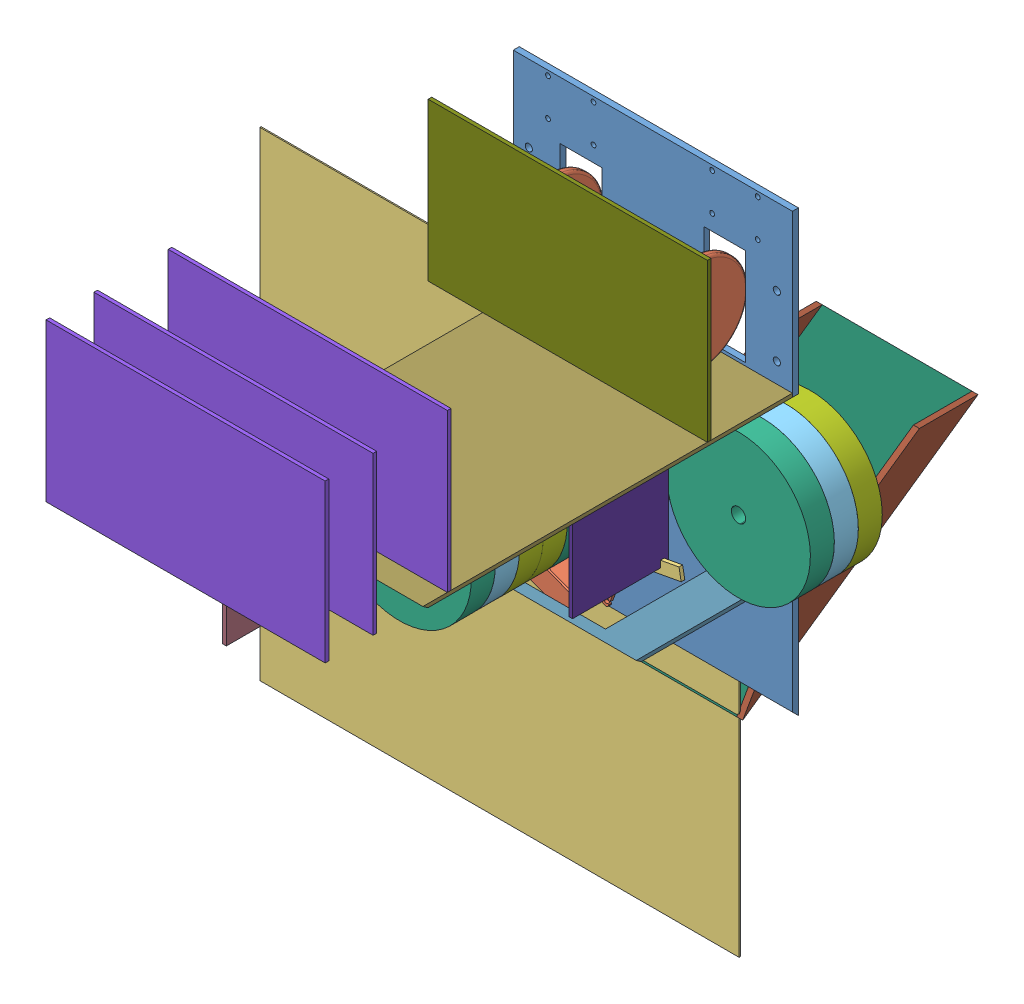
SolidWorks assembly diff_sys4, configuration Default. Lengths in mm.
Overall size (587.66 576.73 602.12).
76 component instances, 41 part files, 74 mates.
Components (placement in the parent):
- diff_base-1: diff_base [Default] at (2.8298 305.3457 326.6792) size (361.16 367.18 5)
- wheel-1: wheel [Default] at (67.3298 304.3457 356.6792) x (0 0.692445 -0.721471) z (-1 0 0) size (80 80 7)
- ground-1: ground [Default] at (-340.1702 216.7923 315.6792) size (400 400 1)
- wheel-2: wheel [Default] at (-52.6702 304.3457 356.6792) x (0 0.692445 -0.721471) z (-1 0 0) size (80 80 7)
- diff_plate-1: diff_plate [Default] at (-5.6702 196.3457 331.6792) size (120 120 3)
- cream_yellow-1: cream_yellow [Default] at (119.3298 196.3457 336.6792) x (0.983664 -0.180016 0) z (0 0 1) size (120 120 20)
- Icing_pink-1: Icing_pink [Default] at (119.3298 196.3457 356.6792) x (0.777887 0.628404 0) z (0 0 1) size (120 120 20)
- sponge_brown-1: sponge_brown [Default] at (119.3298 196.3457 316.6792) size (120 120 20)
- sponge_brown-2: sponge_brown [Default] at (-5.6702 196.3457 334.6792) size (120 120 20)
- Icing_pink-2: Icing_pink [Default] at (-5.6702 196.3457 374.6792) size (120 120 20)
- cream_yellow-2: cream_yellow [Default] at (-5.6702 196.3457 354.6792) x (0.983664 -0.180016 0) z (0 0 1) size (120 120 20)
- sponge_brown-3: sponge_brown [Default] at (-5.6702 196.3457 394.6792) size (120 120 20)
- Icing_pink-3: Icing_pink [Default] at (-5.6702 196.3457 434.6792) size (120 120 20)
- cream_yellow-3: cream_yellow [Default] at (-5.6702 196.3457 414.6792) x (0.983664 -0.180016 0) z (0 0 1) size (120 120 20)
- sponge_brown-5: sponge_brown [Default] at (-5.6702 196.3457 454.6792) x (0.879645 -0.475631 0) z (0 0 1) size (120 120 20)
- diff_layer_3-9: diff_layer_3 [Default] at (-113.6702 393.3457 616.6792) size (233 131.5 3)
- ydlidar x4-1: ydlidar x4 [Défaut] at (33.3597 285.634 646.6792) size (101.5 71 59)
- Raspberry Pi  Camera-1: Raspberry Pi  Camera [Default] at (-15.5914 342.8882 616.6792) x (-1 0 0) z (0 0 -1) size (25 24 6)
- Part11-2: Part11 [Default] at (-53.5079 625.6972 -273.3379) x (1 0 0) z (0 -0.96518 0.261586) size (5 153.68 183.78)
- Part11-5: Part11 [Default] at (76.4921 625.6972 -273.3379) x (1 0 0) z (0 -0.96518 0.261586) size (5 153.68 183.78)
- Part15-1: Part15 [Default] at origin size (187.5 3 308.39)
- Part1-1: Part1 [Default] at (-67.3348 -1575.8564 386.9479) x (-1 0 0) z (0 -0.928525 0.37127) size (3 313.27 227.45)
- Part4-1: Part4 [Default] at (-75.0055 289.3457 402.6792)
- Part5-1: Part5 [Default] at (2.8298 305.3457 331.6792) size (187.5 3 130.37)
- diff_new_conv-1: diff_new_conv [Default] at (-71.1702 56.6686 217.945) x (1 0 0) z (0 0.819827 0.572612) size (131 239.56 3)
- diff_layer_2-1: diff_layer_2 [Default] at (-113.6702 393.3457 399.6792) size (233 131.5 3)
- diff_layer_3-10: diff_layer_3 [Default] at (-113.6702 393.3457 678.6792) size (233 131.5 3)
- diff_layer_3-11: diff_layer_3 [Default] at (119.3298 393.3457 721.6792) x (-1 0 0) z (0 0 -1) size (233 131.5 3)
- filter-1: filter [Default] at origin
- Part2-1: Part2 [Default] at (-16.8692 1325.4742 6580.7646) x (-0.97323 0.229833 0) z (0 0 -1) size (30.96 119.42 80)
- PRUSA 3i horizontal asm-2: PRUSA 3i horizontal asm [Default] at (49.8131 161.8048 504.3442) x (0 1 0) z (-1 0 0) size (67.34 231.9 59.4)
  - lead motor assy-1: lead motor assy [Default] at (-0.8403 21.4836 65.5397) size (60.3 83.9 59.73)
    - x motor lead-1: x motor lead [Default] at (1.0016 21.1815 58.4436) size (38.44 32 28.56)
    - Nema 17 Damper v2-1: Nema 17 Damper v2 [Default] at (1.0013 -26.8185 65.4439) x (0.000014 0 -1) z (-1 0 -0.000014) size (52.04 7.74 51.84)
    - 17HM19-2004S-1: 17HM19-2004S [Default] at (-7.0367 -101.7185 75.8822) x (0.703083 0 -0.711108) z (0.711108 0 0.703083) size (42.24 72 42.24)
      - nema17_shaft_17HM19-2004S-1: nema17_shaft_17HM19-2004S [Default] at (13.0746 21 -1.623) x (-0.412738 0 0.91085) z (-0.91085 0 -0.412738) size (5 72 5)
      - nema17_bottom_17HM19-2004S-1: nema17_bottom_17HM19-2004S [Default] at (13.0746 21 -1.623) x (0.999984 0 0.005702) z (-0.005702 0 0.999984) size (42 12 42)
      - nema17_middle_17HM19-2004S-1: nema17_middle_17HM19-2004S [Default] at (13.0746 29.5 -1.623) x (0.999984 0 0.005702) z (-0.005702 0 0.999984) size (42 31.5 42)
      - nema17_top_17HM19-2004S-1: nema17_top_17HM19-2004S [Default] at (13.0746 61 -1.623) x (0.999984 0 0.005702) z (-0.005702 0 0.999984) size (42 12.6 42)
      - radial ball bearing_68_din_DIN 625 - 625 - 8,SI,NC,8_68-1: radial ball bearing_68_din_DIN 625 - 625 - 8,SI,NC,8_68 [Default] at (13.0746 26 -1.623) x (0 -1 0) z (0 0 1) size (5.01 16 16)
      - radial ball bearing_68_din_DIN 625 - 625 - 8,SI,NC,8_68-2: radial ball bearing_68_din_DIN 625 - 625 - 8,SI,NC,8_68 [Default] at (13.0746 67.1 -1.623) x (0 1 0) z (0 0 1) size (5.01 16 16)
      - countersunk flat head cross recess screw_din_ISO 7046-1 - M3 x 30 - Z --- 30N-1: countersunk flat head cross recess screw_din_ISO 7046-1 - M3 x 30 - Z --- 30N [Default] at (28.4859 21.6 13.9651) x (0 1 0) z (0.546944 0 -0.837169) size (30 5.5 5.5)
      - countersunk flat head cross recess screw_din_ISO 7046-1 - M3 x 30 - Z --- 30N-2: countersunk flat head cross recess screw_din_ISO 7046-1 - M3 x 30 - Z --- 30N [Default] at (28.6627 21.6 -17.0344) x (0 1 0) z (0.546944 0 -0.837169) size (30 5.5 5.5)
      - countersunk flat head cross recess screw_din_ISO 7046-1 - M3 x 30 - Z --- 30N-3: countersunk flat head cross recess screw_din_ISO 7046-1 - M3 x 30 - Z --- 30N [Default] at (-2.5136 21.6 13.7883) x (0 1 0) z (0.546944 0 -0.837169) size (30 5.5 5.5)
      - countersunk flat head cross recess screw_din_ISO 7046-1 - M3 x 30 - Z --- 30N-4: countersunk flat head cross recess screw_din_ISO 7046-1 - M3 x 30 - Z --- 30N [Default] at (-2.3368 21.6 -17.2112) x (0 1 0) z (0.546944 0 -0.837169) size (30 5.5 5.5)
    - 5-8 small-1: 5-8 small [Default] at (1.0016 -17.8185 65.4436) x (1 0 0) z (0 1 0) size (15.39 15.39 20)
  - x lead idler block-1: x lead idler block [Default] at (-3.2253 161.842 204.8708) x (1 0 0) z (0 0 -1) size (40.45 19.18 38.53)
    - x idler lead mirror-1: x idler lead mirror [Default] at (3.3867 7.1769 80.8876) size (39.97 19.18 36.13)
    - instrument ball bearing_68_iso-1: instrument ball bearing_68_iso [ISO 1224 - 100822 - R,8,SI,NC,8_68] at (2.4627 4.6769 72.4222) x (0 -1 0) z (0 0 1) size (7 22 22)
    - brass sleeve 30mm-1: brass sleeve 30mm [Default] at (3.3867 0.1769 52.8876) x (0 0 1) z (-1 0 0) size (11 11 30)
  - liscia da 8 400-1: liscia da 8 400 [Default] at (-22.3386 271.6651 130.9833) x (-0.791136 0 0.611641) z (0 -1 0) size (8 8 167)
  - LeadScrew 8mm x 2mmPitch 500-1: LeadScrew 8mm x 2mmPitch 500 [Default] at (0.1614 12.7651 130.9833) x (-0.096506 0 -0.995332) z (0 -1 0) size (9.24 8.22 159.1)
  - X CHARIOT ASSY-1: X CHARIOT ASSY [Default] at (-13.6593 122.8824 131.0316) x (1 0 0) z (0 -1 0) size (49.4 23.51 36.69)
    - lead x chariot-1: lead x chariot [Default] at (13.8207 -0.0483 62.5173) size (49.08 20 30.38)
    - brass sleeve 30mm-2: brass sleeve 30mm [Default] at (-8.6793 -0.0483 62.5173) x (0.987351 0.158553 0) z (0 0 1) size (11 11 30)
    - LeadScrew Nut 8mm x 2mmPitch (1)-1: LeadScrew Nut 8mm x 2mmPitch (1) [Default] at (13.8207 -0.0483 69.0173) x (-1 0 0) z (0 0 -1) size (22 22 16.05)
    - socket head cap screw_iso-2: socket head cap screw_iso [ISO 4762 M3 x 30 - 18N] at (5.8207 -0.0483 66.0173) x (0 0 1) z (0.923728 0.383049 0) size (33 5.5 5.5)
    - socket head cap screw_iso-3: socket head cap screw_iso [ISO 4762 M3 x 30 - 18N] at (13.8207 7.9517 66.0173) x (0 0 1) z (0.383049 -0.923728 0) size (33 5.5 5.5)
    - socket head cap screw_iso-4: socket head cap screw_iso [ISO 4762 M3 x 30 - 18N] at (21.8207 -0.0483 66.0173) x (0 0 1) z (-0.923728 -0.383049 0) size (33 5.5 5.5)
    - socket head cap screw_iso-5: socket head cap screw_iso [ISO 4762 M3 x 30 - 18N] at (13.8207 -8.0483 66.0173) x (0 0 1) z (-0.383049 0.923728 0) size (33 5.5 5.5)
    - hex thin nut chamfered gradeab_iso-1: hex thin nut chamfered gradeab_iso [ISO - 4035 - M3 - N] at (21.8207 -0.0483 92.5173) x (-0.923728 -0.383049 0) z (0 0 -1) size (5.5 6.35 1.8)
    - hex thin nut chamfered gradeab_iso-2: hex thin nut chamfered gradeab_iso [ISO - 4035 - M3 - N] at (13.8207 -8.0483 92.5173) x (-0.383049 0.923728 0) z (0 0 -1) size (5.5 6.35 1.8)
    - hex thin nut chamfered gradeab_iso-3: hex thin nut chamfered gradeab_iso [ISO - 4035 - M3 - N] at (5.8207 -0.0483 92.5173) x (0.923728 0.383049 0) z (0 0 -1) size (5.5 6.35 1.8)
    - hex thin nut chamfered gradeab_iso-4: hex thin nut chamfered gradeab_iso [ISO - 4035 - M3 - N] at (13.8207 7.9517 92.5173) x (0.383049 -0.923728 0) z (0 0 -1) size (5.5 6.35 1.8)
    - socket head cap screw_iso-8: socket head cap screw_iso [ISO 4762 M3 x 10 - 10N] at (-19.7187 -2.2811 67.5173) x (0 1 0) z (0.395734 0 0.918365) size (13 5.5 5.5)
    - socket head cap screw_iso-9: socket head cap screw_iso [ISO 4762 M3 x 10 - 10N] at (-19.7187 -2.2811 87.5173) x (0 1 0) z (0.6 0 0.8) size (13 5.5 5.5)
    - plain washer 10673 type snl_iso-3: plain washer 10673 type snl_iso [ISO 10673-3.2-S] at (-19.7187 2.9517 67.5173) x (0 1 0) z (0 0 1) size (0.8 7 7)
    - plain washer 10673 type snl_iso-4: plain washer 10673 type snl_iso [ISO 10673-3.2-S] at (-19.7187 2.9517 87.5173) x (0 1 0) z (0 0 1) size (0.8 7 7)
    - hex thin nut chamfered gradeab_iso-8: hex thin nut chamfered gradeab_iso [ISO - 4035 - M3 - N] at (-19.7187 7.5189 67.5173) x (0.918365 0 -0.395734) z (0 -1 0) size (5.5 6.35 1.8)
    - hex thin nut chamfered gradeab_iso-9: hex thin nut chamfered gradeab_iso [ISO - 4035 - M3 - N] at (-19.7187 7.5189 87.5173) x (0.8 0 -0.6) z (0 -1 0) size (5.5 6.35 1.8)
- 2__-1: 2__ [Default] at (7.3125 124.3457 393.3369) x (-0.983293 -0.182029 0) z (0 0 -1) size (34.13 14 8)
- Servo-D-1: Servo-D [По умолчанию] at (16.6754 120.8334 431.3369) x (0.93629 -0.351227 0) z (0.351227 0.93629 0) size (53 41.52 20)
- new_slider-2: new_slider [Default] at (121.6765 56.1345 382.3369) x (0.4455 -0.895282 0) z (0 0 1) size (34.93 81.71 3)
- sponge_brown-6: sponge_brown [Default] at (-5.6702 196.3457 474.6792) size (120 120 20)
- Icing_pink-4: Icing_pink [Default] at (-5.6702 196.3457 514.6792) x (0.777887 0.628404 0) z (0 0 1) size (120 120 20)
- cream_yellow-4: cream_yellow [Default] at (-5.6702 196.3457 494.6792) x (0.983664 -0.180016 0) z (0 0 1) size (120 120 20)
Mates (geometry in assembly coordinates):
- Distance1: distance = 15 mm anti-aligned: plane of wheel-1 through (60.3298 304.3457 356.6792) normal (-1 0 0); plane of diff_base-1 through (45.3298 305.3457 331.6792) normal (1 0 0)
- Distance3: distance = 10 mm anti-aligned: plane of ground-1 through (-340.1702 216.7923 316.6792) normal (0 0 1); plane of diff_base-1 through (2.8298 305.3457 326.6792) normal (0 0 -1)
- Tangent2: tangent anti-aligned: cylinder of wheel-1 through (60.3298 304.3457 356.6792) axis (1 0 0) radius 40; plane of ground-1 through (-340.1702 216.7923 316.6792) normal (0 0 1)
- Distance4: distance = 41 mm: cylinder of wheel-1 through (60.3298 304.3457 356.6792) axis (1 0 0) radius 40; plane of diff_base-1 through (2.8298 345.3457 331.6792) normal (0 -1 0)
- Distance5: distance = 15 mm anti-aligned: plane of diff_base-1 through (-74.6702 305.3457 331.6792) normal (1 0 0); plane of wheel-2 through (-59.6702 304.3457 356.6792) normal (-1 0 0)
- Distance6: distance = 1 mm anti-aligned: plane of diff_base-1 through (2.8298 345.3457 331.6792) normal (0 -1 0); cylinder of wheel-2 through (-59.6702 304.3457 356.6792) axis (1 0 0) radius 40
- Tangent5: tangent anti-aligned: plane of ground-1 through (-340.1702 216.7923 316.6792) normal (0 0 1); cylinder of wheel-2 through (-59.6702 304.3457 356.6792) axis (1 0 0) radius 40
- Coincident16: coincident anti-aligned: plane of ground-1 through (-340.1702 216.7923 316.6792) normal (0 0 1); plane of sponge_brown-1 through (119.3298 196.3457 316.6792) normal (0 0 -1)
- Concentric2: concentric aligned: cylinder of cream_yellow-1 through (119.3298 196.3457 356.6792) axis (0 0 -1) radius 60; cylinder of sponge_brown-1 through (119.3298 196.3457 336.6792) axis (0 0 -1) radius 60
- Coincident17: coincident anti-aligned: plane of cream_yellow-1 through (119.3298 196.3457 336.6792) normal (0 0 -1); plane of sponge_brown-1 through (119.3298 196.3457 336.6792) normal (0 0 1)
- Coincident18: coincident anti-aligned: plane of cream_yellow-1 through (119.3298 196.3457 356.6792) normal (0 0 1); plane of Icing_pink-1 through (119.3298 196.3457 356.6792) normal (0 0 -1)
- Concentric3: concentric aligned: cylinder of cream_yellow-1 through (119.3298 196.3457 356.6792) axis (0 0 -1) radius 60; cylinder of Icing_pink-1 through (119.3298 196.3457 376.6792) axis (0 0 -1) radius 60
- Coincident24: coincident: line of diff_base-1 through (59.8298 196.3457 326.6792) axis (0 -1 0); plane of ground-1 through (59.8298 216.7923 316.6792) normal (1 0 0)
- Concentric4: concentric aligned: cylinder of sponge_brown-2 through (-5.6702 196.3457 354.6792) axis (0 0 -1) radius 60; cylinder of cream_yellow-2 through (-5.6702 196.3457 374.6792) axis (0 0 -1) radius 60
- Concentric5: concentric aligned: cylinder of Icing_pink-2 through (-5.6702 196.3457 394.6792) axis (0 0 -1) radius 60; cylinder of cream_yellow-2 through (-5.6702 196.3457 374.6792) axis (0 0 -1) radius 60
- Coincident46: coincident anti-aligned: plane of sponge_brown-2 through (-5.6702 196.3457 354.6792) normal (0 0 1); plane of cream_yellow-2 through (-5.6702 196.3457 354.6792) normal (0 0 -1)
- Coincident47: coincident anti-aligned: plane of Icing_pink-2 through (-5.6702 196.3457 374.6792) normal (0 0 -1); plane of cream_yellow-2 through (-5.6702 196.3457 374.6792) normal (0 0 1)
- Coincident48: coincident anti-aligned: plane of diff_plate-1 through (-5.6702 196.3457 334.6792) normal (0 0 1); plane of sponge_brown-2 through (-5.6702 196.3457 334.6792) normal (0 0 -1)
- Concentric6: concentric aligned: cylinder of diff_plate-1 through (-5.6702 196.3457 334.6792) axis (0 0 -1) radius 60; cylinder of sponge_brown-2 through (-5.6702 196.3457 354.6792) axis (0 0 -1) radius 60
- Concentric7: concentric aligned: cylinder of sponge_brown-3 through (-5.6702 196.3457 414.6792) axis (0 0 -1) radius 60; cylinder of cream_yellow-3 through (-5.6702 196.3457 434.6792) axis (0 0 -1) radius 60
- Concentric8: concentric aligned: cylinder of Icing_pink-3 through (-5.6702 196.3457 454.6792) axis (0 0 -1) radius 60; cylinder of cream_yellow-3 through (-5.6702 196.3457 434.6792) axis (0 0 -1) radius 60
- Coincident49: coincident anti-aligned: plane of sponge_brown-3 through (-5.6702 196.3457 414.6792) normal (0 0 1); plane of cream_yellow-3 through (-5.6702 196.3457 414.6792) normal (0 0 -1)
- Coincident50: coincident anti-aligned: plane of Icing_pink-3 through (-5.6702 196.3457 434.6792) normal (0 0 -1); plane of cream_yellow-3 through (-5.6702 196.3457 434.6792) normal (0 0 1)
- Coincident51: coincident anti-aligned: plane of Icing_pink-2 through (-5.6702 196.3457 394.6792) normal (0 0 1); plane of sponge_brown-3 through (-5.6702 196.3457 394.6792) normal (0 0 -1)
- Concentric9: concentric aligned: cylinder of Icing_pink-2 through (-5.6702 196.3457 394.6792) axis (0 0 -1) radius 60; cylinder of sponge_brown-3 through (-5.6702 196.3457 414.6792) axis (0 0 -1) radius 60
- Coincident56: coincident anti-aligned: plane of Icing_pink-3 through (-5.6702 196.3457 454.6792) normal (0 0 1); plane of sponge_brown-5 through (-5.6702 196.3457 454.6792) normal (0 0 -1)
- Concentric14: concentric aligned: cylinder of Icing_pink-3 through (-5.6702 196.3457 454.6792) axis (0 0 -1) radius 60; cylinder of sponge_brown-5 through (-5.6702 196.3457 474.6792) axis (0 0 -1) radius 60
- InPlace11: in place: plane of diff_base-1 through (2.8298 305.3457 331.6792) normal (0 0 1); plane of ? through (0 0 331.6792) normal (0 0 1); moOrthogonalPlaneRef_w of diff_base-1 through (2.8298 305.3457 331.6792) normal (0 0 1); plane of ? through (0 0 331.6792) normal (0 1 0); plane of diff_base-1 through (2.8298 305.3457 331.6792) normal (0 0 1); plane of ? through (0 0 331.6792) normal (1 0 0); plane of diff_base-1 through (2.8298 305.3457 331.6792) normal (0 0 1); unknown of Part5-1
- Coincident132: coincident aligned: plane of diff_base-1; plane of Part5-1
- Coincident133: coincident aligned: moOrthogonalPlaneRef_w of diff_base-1 through (2.8298 305.3457 331.6792) normal (0 1 0); plane of Part5-1 through (2.8298 305.3457 331.6792) normal (0 1 0)
- Coincident134: coincident anti-aligned: moOrthogonalPlaneRef_w of diff_base-1 through (2.8298 305.3457 331.6792) normal (-1 0 0); plane of Part5-1 through (2.8298 305.3457 331.6792) normal (1 0 0)
- Coincident123: coincident anti-aligned: plane of diff_base-1 through (2.8298 305.3457 331.6792) normal (0 0 1); plane of diff_plate-1 through (-5.6702 196.3457 331.6792) normal (0 0 -1)
- Coincident125: coincident anti-aligned: plane of Part11-2 through (-66.1702 127.8457 121.2776) normal (0 1 0); plane of Part1-1 through (-68.1702 127.8457 747.7135) normal (0 -1 0)
- Distance13: distance = 1 mm: line of Part11-2 through (-66.1702 -9.3319 317.6792) axis (-1 0 0); plane of ground-1 through (-340.1702 216.7923 316.6792) normal (0 0 1)
- Coincident130: coincident anti-aligned: plane of Part11-5 through (63.8298 127.8457 121.2776) normal (0 1 0); plane of Part1-1 through (-68.1702 127.8457 747.7135) normal (0 -1 0)
- Coincident137: coincident aligned: line of Part11-2 through (-66.1702 -9.3319 317.6792) axis (-1 0 0); line of Part11-5 through (63.8298 -9.3319 317.6792) axis (-1 0 0)
- Distance14: distance = 125 mm anti-aligned: plane of Part11-5 through (58.8298 625.6972 -273.3379) normal (-1 0 0); plane of Part11-2 through (-66.1702 625.6972 -273.3379) normal (1 0 0)
- Tangent6: tangent: circle of diff_base-1; plane of Part1-1 through (-68.1702 258.8457 747.7135) normal (1 0 0)
- Coincident145: coincident aligned: plane of Part11-2 through (-71.1702 625.6972 -273.3379) normal (-1 0 0); plane of Part1-1 through (-71.1702 127.8457 747.7135) normal (-1 0 0)
- Coincident149: coincident anti-aligned: plane of Part11-2 through (-66.1702 127.8457 121.2776) normal (0 -0.819827 -0.572612); plane of diff_new_conv-1 through (-71.1702 59.1281 219.6628) normal (0 0.819827 0.572612)
- Distance15: distance = 1 mm: line of diff_new_conv-1 through (-71.1702 -9.3319 317.6792) axis (1 0 0); plane of ground-1 through (-340.1702 216.7923 316.6792) normal (0 0 1)
- Distance16: distance = 68 mm anti-aligned: plane of diff_layer_2-1 through (-113.6702 393.3457 399.6792) normal (0 0 -1); plane of diff_base-1 through (2.8298 305.3457 331.6792) normal (0 0 1)
- Coincident154: coincident aligned: plane of diff_base-1 through (2.8298 393.3457 331.6792) normal (0 1 0); plane of diff_layer_2-1 through (-113.6702 393.3457 402.6792) normal (0 1 0)
- Coincident155: coincident aligned: plane of diff_base-1 through (-113.6702 305.3457 331.6792) normal (-1 0 0); plane of diff_layer_2-1 through (-113.6702 393.3457 402.6792) normal (-1 0 0)
- Coincident157: coincident anti-aligned: plane of Raspberry Pi  Camera-1 through (-15.5914 342.8882 616.6792) normal (0 0 1); plane of diff_layer_3-9 through (-113.6702 393.3457 616.6792) normal (0 0 -1)
- Coincident158: coincident aligned: plane of diff_base-1 through (-113.6702 305.3457 331.6792) normal (-1 0 0); plane of diff_layer_3-9 through (-113.6702 393.3457 619.6792) normal (-1 0 0)
- Coincident159: coincident aligned: plane of diff_base-1 through (2.8298 393.3457 331.6792) normal (0 1 0); plane of diff_layer_3-9 through (-113.6702 393.3457 619.6792) normal (0 1 0)
- Distance17: distance = 347 mm anti-aligned: plane of diff_base-1 through (2.8298 305.3457 331.6792) normal (0 0 1); plane of diff_layer_3-10 through (-113.6702 393.3457 678.6792) normal (0 0 -1)
- Coincident161: coincident aligned: plane of diff_base-1 through (-113.6702 305.3457 331.6792) normal (-1 0 0); plane of diff_layer_3-10 through (-113.6702 393.3457 681.6792) normal (-1 0 0)
- Coincident162: coincident aligned: plane of diff_base-1 through (2.8298 393.3457 331.6792) normal (0 1 0); plane of diff_layer_3-10 through (-113.6702 393.3457 681.6792) normal (0 1 0)
- Distance18: distance = 40 mm aligned: plane of diff_layer_3-11 through (119.3298 393.3457 718.6792) normal (0 0 -1); plane of diff_layer_3-10 through (-113.6702 393.3457 678.6792) normal (0 0 -1)
- Coincident164: coincident aligned: plane of diff_base-1 through (2.8298 393.3457 331.6792) normal (0 1 0); plane of diff_layer_3-11 through (119.3298 393.3457 718.6792) normal (0 1 0)
- Coincident165: coincident aligned: plane of diff_base-1 through (-113.6702 305.3457 331.6792) normal (-1 0 0); plane of diff_layer_3-11 through (-113.6702 393.3457 718.6792) normal (-1 0 0)
- Coincident180: coincident anti-aligned: plane of Part1-1 through (-71.1702 127.8457 747.7135) normal (-1 0 0); plane of PRUSA 3i horizontal asm-2/X CHARIOT ASSY-1/lead x chariot-1 through (-71.1702 131.9661 473.9792) normal (1 0 0)
- Coincident181: coincident anti-aligned: plane of diff_base-1 through (2.8298 305.3457 331.6792) normal (0 0 1); plane of PRUSA 3i horizontal asm-2/x lead idler block-1/x idler lead mirror-1 through (17.4972 204.8552 331.6792) normal (0 0 -1)
- Coincident186: coincident anti-aligned: plane of ydlidar x4-1 through (33.3597 285.634 678.6792) normal (0 0 1); plane of diff_layer_3-10 through (-113.6702 393.3457 678.6792) normal (0 0 -1)
- Coincident187: coincident anti-aligned: plane of diff_layer_3-9 through (-113.6702 393.3457 619.6792) normal (0 0 1); plane of ydlidar x4-1 through (33.3597 285.634 619.6792) normal (0 0 -1)
- Concentric15: concentric aligned: cylinder of 2__-1 through (7.3125 124.3457 388.3369) axis (0 0 1) radius 3; cylinder of Servo-D-1 through (7.3125 124.3457 389.8369) axis (0 0 1) radius 3
- Coincident188: coincident anti-aligned: plane of 2__-1 through (7.3125 124.3457 393.3369) normal (0 0 1); plane of Servo-D-1 through (7.3125 124.3457 393.3369) normal (0 0 -1)
- Concentric22: concentric aligned: cylinder of diff_base-1 through (119.3298 196.3457 331.6792) axis (0 0 -1) radius 62.5; cylinder of sponge_brown-1 through (119.3298 196.3457 336.6792) axis (0 0 -1) radius 60
- Coincident201: coincident anti-aligned: plane of diff_base-1 through (2.8298 305.3457 331.6792) normal (0 0 1); plane of Part1-1 through (-67.3348 -1575.8564 331.6792) normal (0 0 -1)
- Coincident202: coincident anti-aligned: plane of Part15-1 through (119.3298 258.8457 892.3632) normal (0 -1 0); plane of Part1-1 through (-68.1702 258.8457 747.7135) normal (0 1 0)
- Coincident203: coincident aligned: plane of Part1-1 through (-71.1702 127.8457 747.7135) normal (-1 0 0); plane of diff_new_conv-1 through (-71.1702 127.8457 121.2776) normal (-1 0 0)
- Concentric28: concentric anti-aligned: cylinder of diff_base-1; cylinder of diff_plate-1 through (-5.6702 196.3457 334.6792) axis (0 0 -1) radius 60
- Coincident211: coincident anti-aligned: plane of 2__-1 through (36.8113 129.8065 385.3369) normal (0 0 -1); plane of new_slider-2 through (7.3125 124.3457 385.3369) normal (0 0 1)
- Concentric29: concentric anti-aligned: cylinder of 2__-1 through (7.3125 124.3457 388.3369) axis (0 0 1) radius 3; cylinder of new_slider-2 through (7.3125 124.3457 385.3369) axis (0 0 -1) radius 2.5
- Concentric30: concentric anti-aligned: cylinder of 2__-1 through (31.8948 128.8964 385.3369) axis (0 0 1) radius 1.5; cylinder of new_slider-2 through (31.8948 128.8964 385.3369) axis (0 0 -1) radius 1.5
- Concentric32: concentric anti-aligned: cylinder of new_slider-2 through (7.3125 124.3457 385.3369) axis (0 0 -1) radius 2.5
- Coincident212: coincident anti-aligned: plane of sponge_brown-6 through (-5.6702 196.3457 494.6792) normal (0 0 1); plane of cream_yellow-4 through (-5.6702 196.3457 494.6792) normal (0 0 -1)
- Coincident213: coincident anti-aligned: plane of Icing_pink-4 through (-5.6702 196.3457 514.6792) normal (0 0 -1); plane of cream_yellow-4 through (-5.6702 196.3457 514.6792) normal (0 0 1)
- Concentric33: concentric aligned: cylinder of sponge_brown-6 through (-5.6702 196.3457 494.6792) axis (0 0 -1) radius 60; cylinder of cream_yellow-4 through (-5.6702 196.3457 514.6792) axis (0 0 -1) radius 60
- Concentric34: concentric aligned: cylinder of Icing_pink-4 through (-5.6702 196.3457 534.6792) axis (0 0 -1) radius 60; cylinder of cream_yellow-4 through (-5.6702 196.3457 514.6792) axis (0 0 -1) radius 60
- Concentric35: concentric aligned: cylinder of sponge_brown-5 through (-5.6702 196.3457 474.6792) axis (0 0 -1) radius 60; cylinder of sponge_brown-6 through (-5.6702 196.3457 494.6792) axis (0 0 -1) radius 60
- Coincident214: coincident anti-aligned: plane of sponge_brown-5 through (-5.6702 196.3457 474.6792) normal (0 0 1); plane of sponge_brown-6 through (-5.6702 196.3457 474.6792) normal (0 0 -1)
